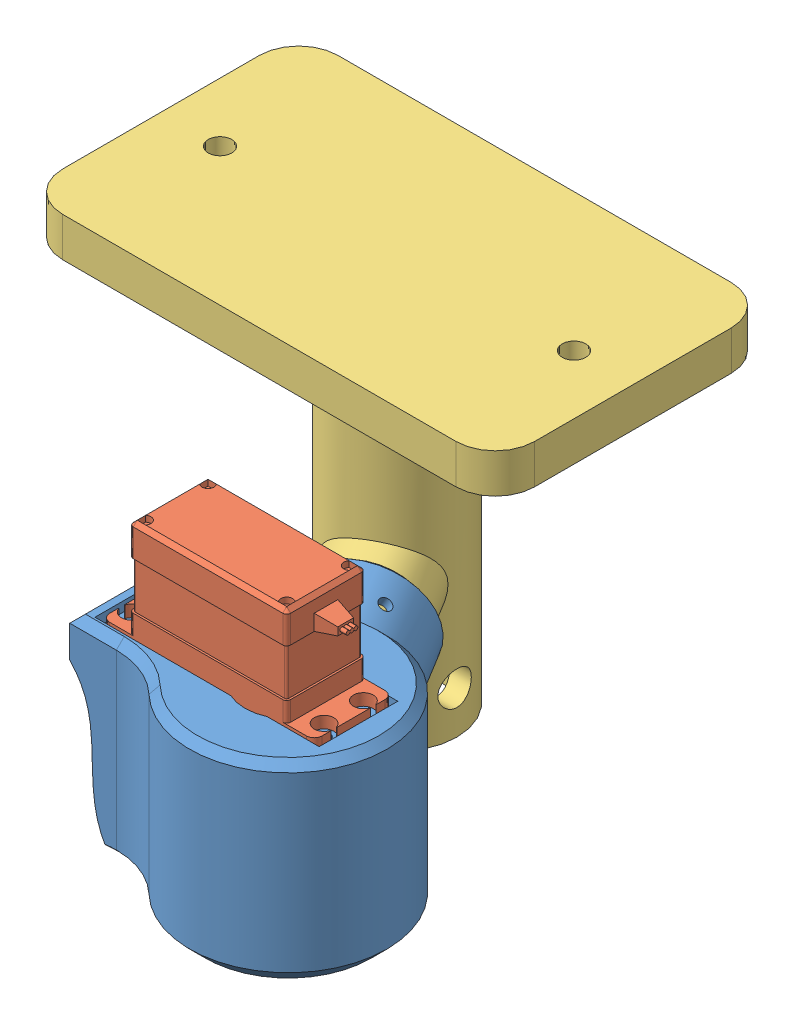
SolidWorks assembly Testbed_clamp, configuration Default. Lengths in mm.
Overall size (120 100 119.65).
3 component instances, 3 part files, 4 mates.
Components (placement in the parent):
- Steer_motor_holder_rear-1: Steer_motor_holder_rear [Default] at (-51.9253 -24.2648 40.5162) size (68.1 50 74.21)
- RKI-1203 Ultra Torque Metal Gear 35kgcm Coreless SERVO.step-1: RKI-1203 Ultra Torque Metal Gear 35kgcm Coreless SERVO.step [Default] at (-56.5313 51.2352 40.2662) x (-1 0 0) z (0 0 1) size (54 42 20.06)
- Testbed_top-1: Testbed_top [Default] at (-77.839 65.7352 -19.0842) x (1 0 0) z (0 1 0) size (120 75.1 100)
Mates (geometry in assembly coordinates):
- Coincident1: coincident anti-aligned: plane of Steer_motor_holder_rear-1 through (-51.9253 23.2352 40.5162) normal (0 1 0); plane of RKI-1203 Ultra Torque Metal Gear 35kgcm Coreless SERVO.step-1 through (-76.5313 23.2352 50.2662) normal (0 -1 0)
- Concentric1: concentric anti-aligned: cylinder of Steer_motor_holder_rear-1 through (-81.0313 -9.2648 45.2662) axis (0 1 0) radius 1.5; circle of RKI-1203 Ultra Torque Metal Gear 35kgcm Coreless SERVO.step-1
- Concentric2: concentric aligned: cylinder of Steer_motor_holder_rear-1 through (-32.0313 -9.2648 45.2662) axis (0 1 0) radius 1.5; cylinder of RKI-1203 Ultra Torque Metal Gear 35kgcm Coreless SERVO.step-1 through (-32.0313 23.2352 45.2662) axis (0 1 0) radius 2.515
- Distance1: distance = 40 mm anti-aligned: plane of Steer_motor_holder_rear-1 through (-77.0661 25.7352 7.9516) normal (0 1 0); plane of Testbed_top-1 through (-77.839 65.7352 -19.0842) normal (0 -1 0)
